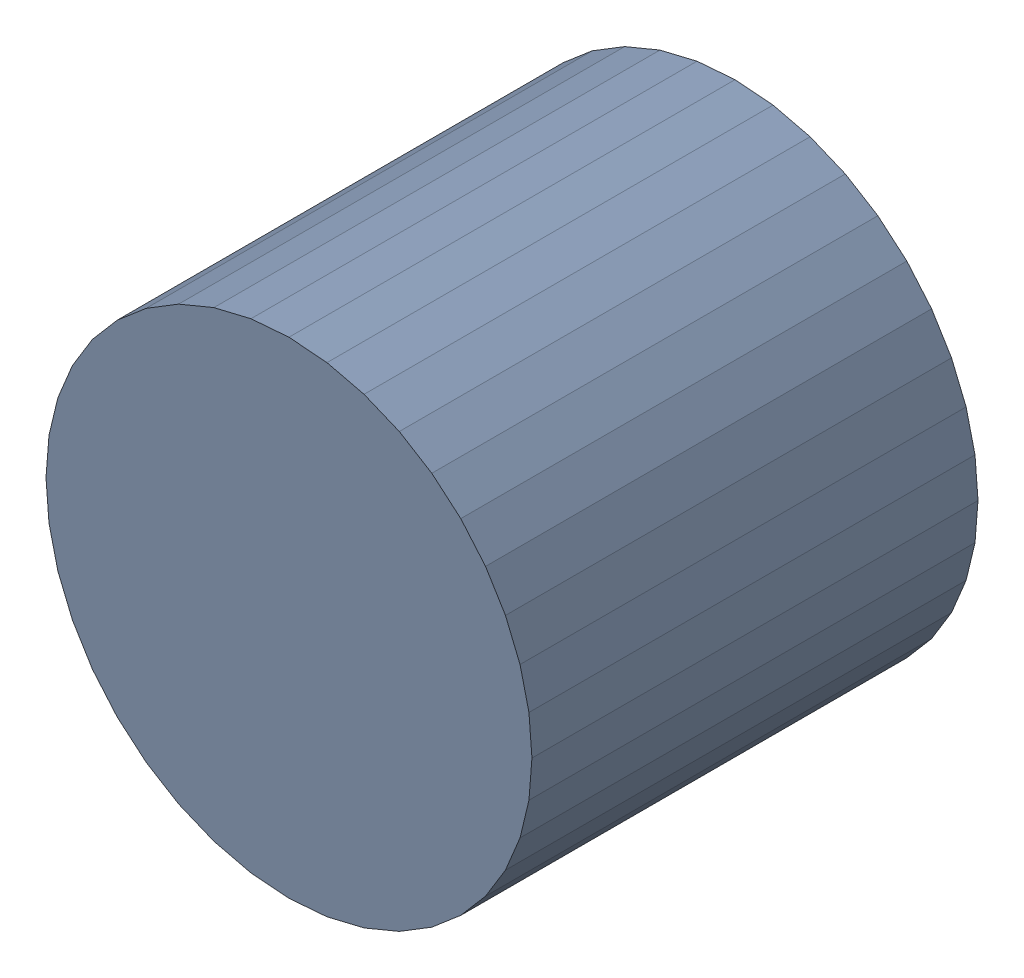
SolidWorks assembly C10_Motor_9Kanaloa_v2.0.0_Motor, configuration Default. Lengths in mm.
Overall size (6.32 6.32 5.8).
2 component instances, 1 part files, 0 mates.
Components (placement in the parent):
- 352892112-1: 352892112 [Default] at (46.169 155.194 0) size (6.32 6.32 5.8)
  - Extruded_11-1: Extruded_11 [Default] at origin size (6.32 6.32 5.8)
